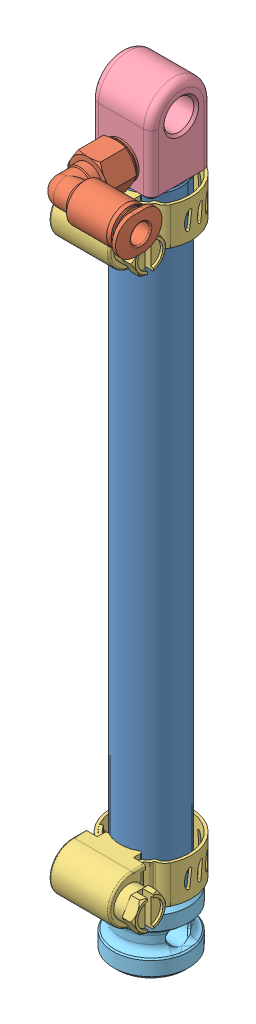
SolidWorks assembly AARL_QR_PN_PA_FR_SH_EX-Extensor, configuration Default. Lengths in mm.
Overall size (24.22 161.92 31.28).
6 component instances, 5 part files, 15 mates.
Components (placement in the parent):
- AARL_QR_PN_PA_FR_SH_EX_001-1: AARL_QR_PN_PA_FR_SH_EX_001 [Resting] at origin size (12.7 130.18 12.7)
- AARL_Puppy_18_02_57_010-QSML-M3-4-1: AARL_Puppy_18_02_57_010-QSML-M3-4 [Default] at (0 69.85 17.85) x (1 0 0) z (0 0 -1) size (20.32 8 18.9)
- AARL_Puppy_18_02_57_011-5388K140_Hose-Clamp-1: AARL_Puppy_18_02_57_011-5388K140_Hose-Clamp [5388K14] at (0 60.1345 0) x (1 0 0) z (0 -1 0) size (19.43 23.71 9.91)
- AARL_Puppy_18_02_57_011-5388K140_Hose-Clamp-2: AARL_Puppy_18_02_57_011-5388K140_Hose-Clamp [5388K14] at (0 -60.1345 0) x (1 0 0) z (0 -1 0) size (19.43 23.71 9.91)
- AARL_QR_PN_EP_001-1: AARL_QR_PN_EP_001 [Default] at (0 77.7875 0) x (0 0 1) z (-1 0 0) size (12.7 31.75 12.7)
- AARL_QR_PN_EP_002-1: AARL_QR_PN_EP_002 [Default] at (0 -65.0875 0) x (-1 0 0) z (0 0 1) size (15.88 25.4 15.88)
Mates (geometry in assembly coordinates):
- Concentric1: concentric aligned: cylinder of AARL_QR_PN_PA_FR_SH_EX_001-1 through (0 11.6086 0) axis (0 1 0) radius 4.7625; cylinder of AARL_QR_PN_EP_001-1 through (0 87.3315 0) axis (0 1 0) radius 4.3656
- Parallel1: parallel aligned: plane of AARL_QR_PN_EP_001-1 through (-6.35 65.0875 6.35) normal (0 0 1)
- Coincident2: coincident anti-aligned: plane of AARL_QR_PN_PA_FR_SH_EX_001-1 through (4.7625 65.0875 0) normal (0 1 0); plane of AARL_QR_PN_EP_001-1 through (-6.35 65.0875 -6.35) normal (0 -1 0)
- Concentric2: concentric anti-aligned: cylinder of AARL_QR_PN_PA_FR_SH_EX_001-1 through (0 11.6086 0) axis (0 1 0) radius 4.7625; cylinder of AARL_QR_PN_EP_002-1 through (0 -72.8252 0) axis (0 -1 0) radius 4.3656
- Coincident3: coincident anti-aligned: plane of AARL_QR_PN_PA_FR_SH_EX_001-1 through (6.35 -65.0875 0) normal (0 -1 0); plane of AARL_QR_PN_EP_002-1 through (-4.3656 -65.0875 0) normal (0 1 0)
- Parallel2: parallel anti-aligned: cylinder of AARL_QR_PN_EP_001-1 through (-6.35 77.7875 0) axis (1 0 0) radius 3.175; cylinder of AARL_QR_PN_EP_002-1 through (7.9375 -71.4375 0) axis (-1 0 0) radius 2.3813
- Concentric4: concentric aligned: cylinder of AARL_Puppy_18_02_57_010-QSML-M3-4-1 through (0 69.85 6.35) axis (0 0 1) radius 1.5; cylinder of AARL_QR_PN_EP_001-1 through (0 69.85 6.35) axis (0 0 1) radius 2.0193
- Coincident4: coincident anti-aligned: plane of AARL_Puppy_18_02_57_010-QSML-M3-4-1 through (0 69.85 6.35) normal (0 0 -1); plane of AARL_QR_PN_EP_001-1 through (-6.35 65.0875 6.35) normal (0 0 1)
- Parallel3: parallel anti-aligned: plane of AARL_Puppy_18_02_57_010-QSML-M3-4-1 through (-2.3094 73.85 13.4056) normal (0 1 0); plane of AARL_QR_PN_EP_001-1 through (-6.35 65.0875 -6.35) normal (0 -1 0)
- Concentric5: concentric aligned: cylinder of AARL_QR_PN_PA_FR_SH_EX_001-1 through (0 11.6086 0) axis (0 1 0) radius 6.35; cylinder of AARL_Puppy_18_02_57_011-5388K140_Hose-Clamp-1 through (0 56.1658 0) axis (0 1 0) radius 7.9375
- Coincident6: coincident aligned: plane of AARL_Puppy_18_02_57_011-5388K140_Hose-Clamp-1 through (6.35 60.1345 10.2337) normal (1 0 0); plane of AARL_QR_PN_EP_001-1 through (6.35 77.7875 0) normal (1 0 0)
- Coincident7: coincident anti-aligned: plane of AARL_Puppy_18_02_57_011-5388K140_Hose-Clamp-1 through (0 65.0875 0) normal (0 1 0); plane of AARL_QR_PN_EP_001-1 through (-6.35 65.0875 -6.35) normal (0 -1 0)
- Concentric6: concentric aligned: cylinder of AARL_QR_PN_PA_FR_SH_EX_001-1 through (0 11.6086 0) axis (0 1 0) radius 6.35; cylinder of AARL_Puppy_18_02_57_011-5388K140_Hose-Clamp-2 through (0 -64.1033 0) axis (0 1 0) radius 7.9375
- Coincident8: coincident aligned: plane of AARL_Puppy_18_02_57_011-5388K140_Hose-Clamp-1 through (6.35 60.1345 10.2337) normal (1 0 0); plane of AARL_Puppy_18_02_57_011-5388K140_Hose-Clamp-2 through (6.35 -60.1345 10.2337) normal (1 0 0)
- Coincident9: coincident anti-aligned: plane of AARL_Puppy_18_02_57_011-5388K140_Hose-Clamp-2 through (0 -65.0875 0) normal (0 -1 0); plane of AARL_QR_PN_EP_002-1 through (-4.3656 -65.0875 0) normal (0 1 0)
